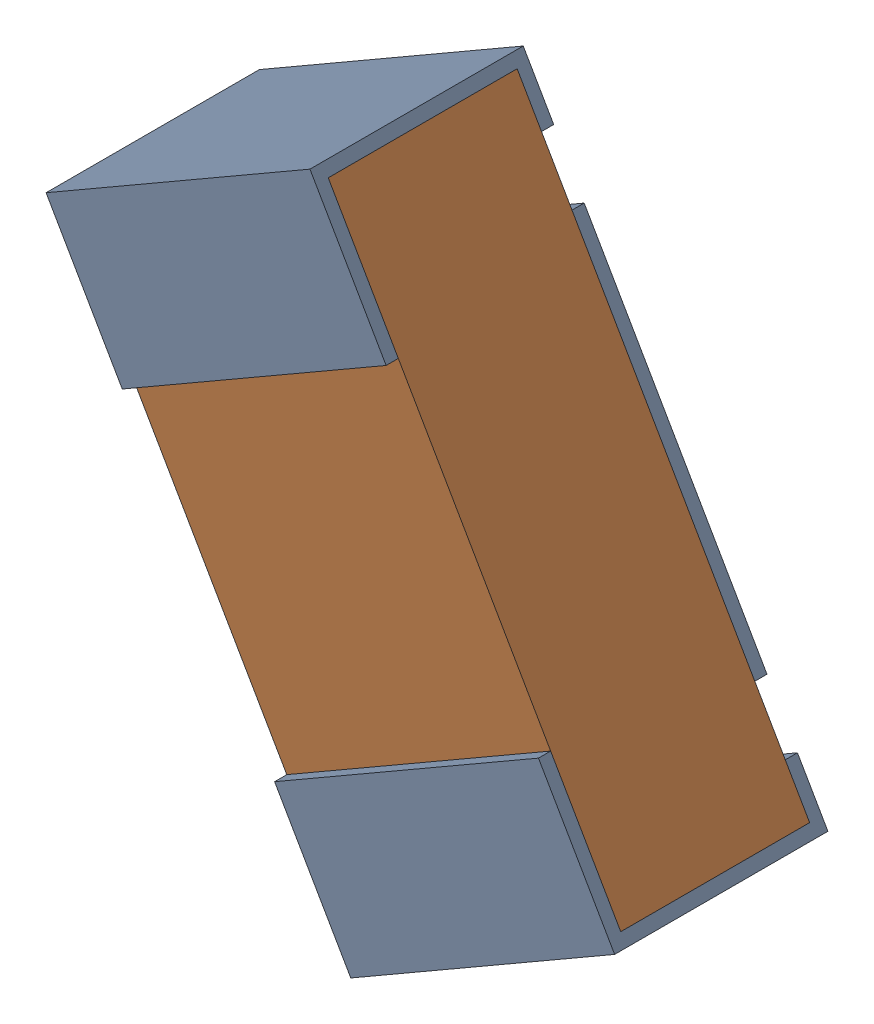
SolidWorks assembly R13, configuration Default. Lengths in mm.
Overall size (0.93 1.12 0.35).
3 component instances, 2 part files, 0 mates.
Components (placement in the parent):
- R13-subassembly-1-1: R13-subassembly-1 [Default] at (-3.821 -3.8771 -1.6307) x (-0.5 0.866025 0) z (-0.866025 -0.5 0) size (1 0.35 0.5)
  - 0402 resistor-1: 0402 resistor [Default] at origin size (1 0.35 0.5)
  - 0402 resistor-1-1: 0402 resistor-1 [Default] at origin size (0.96 0.31 0.5)
